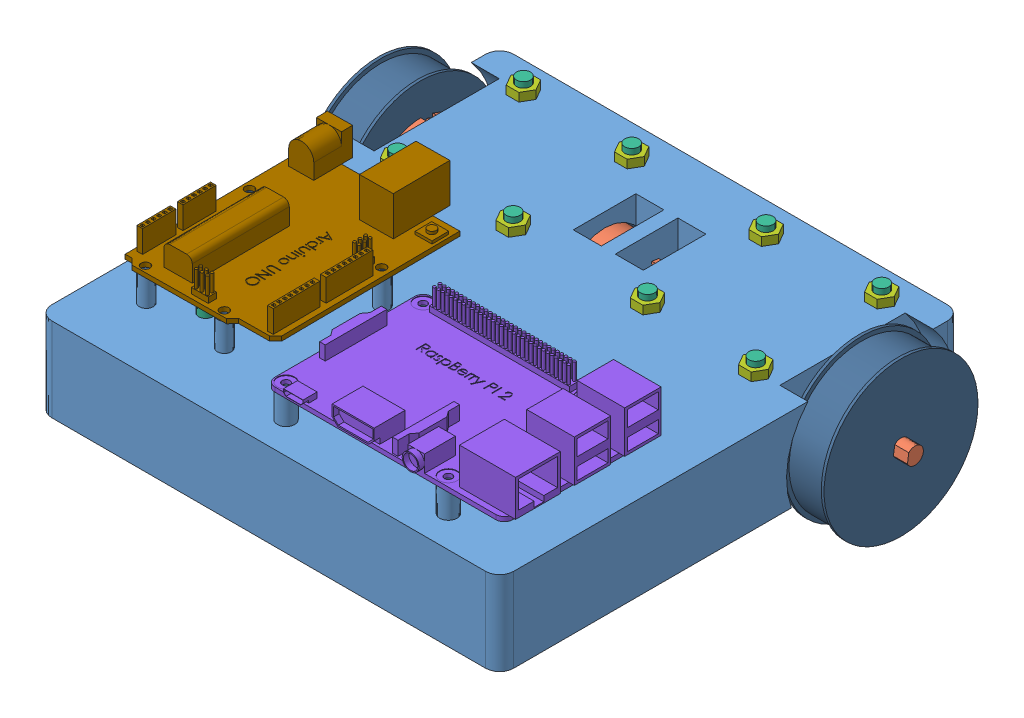
SolidWorks assembly base_robot2_ass, configuration Défaut. Lengths in mm.
Overall size (196.8 85.06 170.96).
31 component instances, 10 part files, 62 mates.
Components (placement in the parent):
- base_robot2_model-1: base_robot2_model [Défaut] at (-7.2062 -14.7881 165) size (165 40 165)
- moteur_IG320100-1: moteur_IG320100 [Défaut] at (-74.68 -4.7881 115) x (0 0.804168 0.594401) z (-1 0 0) size (32 32 94.7)
- moteur_IG320100-2: moteur_IG320100 [Défaut] at (60.2677 -4.7881 115) x (0 0.988328 -0.152341) z (1 0 0) size (32 32 94.7)
- patin_robot2_model-1: patin_robot2_model [Défaut] at (-59.7062 -24.7881 217.5) size (40 10 30)
- patin_robot2_model-2: patin_robot2_model [Défaut] at (45.2938 -24.7881 217.5) size (40 10 30)
- support_moteur_30mm-1: support_moteur_30mm [Défaut] at (11.7938 -4.7881 115) x (1 0 0) z (0 0 -1) size (10 9 52.36)
- support_moteur_30mm-2: support_moteur_30mm [Défaut] at (-26.2062 -4.7881 115) x (-1 0 0) z (0 0 1) size (10 9 52.36)
- support_moteur_32.02mm-1: support_moteur_32.02mm [Défaut] at (61.7938 -4.7881 115) x (-1 0 0) z (0 0 1) size (10 10.01 55.01)
- support_moteur_32.02mm-2: support_moteur_32.02mm [Défaut] at (-76.2062 -4.7881 115) x (1 0 0) z (0 0 -1) size (10 10.01 55.01)
- vis_5mm-1: vis_5mm [Défaut] at (16.7938 -19.7881 93.8197) x (0.187636 0 -0.982239) z (-0.982239 0 -0.187636) size (8 42.5 8)
- vis_5mm-2: vis_5mm [Défaut] at (56.7938 -19.7881 92.4972) x (-0.262741 0 -0.964866) z (-0.964866 0 0.262741) size (8 42.5 8)
- vis_5mm-3: vis_5mm [Défaut] at (16.7938 -19.7881 136.1803) x (0.587771 0 -0.809028) z (-0.809028 0 -0.587771) size (8 42.5 8)
- vis_5mm-4: vis_5mm [Défaut] at (56.7938 -19.7881 137.5028) x (-0.993067 0 0.117546) z (0.117546 0 0.993067) size (8 42.5 8)
- vis_5mm-5: vis_5mm [Défaut] at (-31.2062 -19.7881 136.1803) x (0.909957 0 -0.414702) z (-0.414702 0 -0.909957) size (8 42.5 8)
- vis_5mm-6: vis_5mm [Défaut] at (-71.2062 -19.7881 137.5028) x (0.689074 0 -0.724691) z (-0.724691 0 -0.689074) size (8 42.5 8)
- vis_5mm-7: vis_5mm [Défaut] at (-31.2062 -19.7881 93.8197) x (0.478965 0 -0.877834) z (-0.877834 0 -0.478965) size (8 42.5 8)
- vis_5mm-8: vis_5mm [Défaut] at (-71.2062 -19.7881 92.4972) x (0.586817 0 -0.80972) z (-0.80972 0 -0.586817) size (8 42.5 8)
- vis_5mm-9: vis_5mm [Défaut] at (45.2938 -19.7881 217.5) x (0.470882 0 0.882196) z (0.882196 0 -0.470882) size (8 42.5 8)
- vis_5mm-10: vis_5mm [Défaut] at (-59.7062 -19.7881 217.5) x (-0.905597 0 -0.424138) z (-0.424138 0 0.905597) size (8 42.5 8)
- ecrou_5mm_model-1: ecrou_5mm_model [Défaut] at (56.7938 15.2119 92.4972) size (9 3 7.79)
- raspberry-1: raspberry [Défaut] at (26.6692 25.2119 211.6943) size (89 17.6 58)
- arduino-1: arduino [Défaut] at (-54.4822 25.2119 192.998) x (0.009951 0 0.99995) z (-0.99995 0 0.009951) size (74.8 15.6 53.3)
- ecrou_5mm_model-2: ecrou_5mm_model [Défaut] at (-31.2062 15.2119 93.8197) size (9 3 7.79)
- ecrou_5mm_model-3: ecrou_5mm_model [Défaut] at (16.7938 15.2119 136.1803) size (9 3 7.79)
- ecrou_5mm_model-4: ecrou_5mm_model [Défaut] at (56.7938 15.2119 137.5028) size (9 3 7.79)
- ecrou_5mm_model-5: ecrou_5mm_model [Défaut] at (-31.2062 15.2119 136.1803) size (9 3 7.79)
- ecrou_5mm_model-6: ecrou_5mm_model [Défaut] at (16.7938 15.2119 93.8197) size (9 3 7.79)
- ecrou_5mm_model-7: ecrou_5mm_model [Défaut] at (-71.2062 15.2119 137.5028) size (9 3 7.79)
- ecrou_5mm_model-8: ecrou_5mm_model [Défaut] at (-71.2062 15.2119 92.4972) size (9 3 7.79)
- roue_imprimer_model-2: roue_imprimer_model [Défaut] at (-95.6062 -4.7881 115) x (1 0 0) z (0 0.804168 0.594401) size (15 55 55)
- roue_imprimer_model-3: roue_imprimer_model [Défaut] at (76.1938 -4.7881 115) x (1 0 0) z (0 -0.988328 0.152341) size (15 55 55)
Mates (geometry in assembly coordinates):
- Coaxiale1: concentric aligned: cylinder of base_robot2_model-1 through (-52.7062 -4.7881 115) axis (-1 0 0) radius 16.01; cylinder of moteur_IG320100-1 through (-95.28 -4.7881 115) axis (-1 0 0) radius 16
- Coïncidente1: coincident anti-aligned: plane of base_robot2_model-1 through (-52.7062 -4.7881 115) normal (-1 0 0); plane of moteur_IG320100-1 through (-52.7062 -4.7881 115) normal (1 0 0)
- Coaxiale3: concentric aligned: cylinder of base_robot2_model-1 through (38.2938 -4.7881 115) axis (1 0 0) radius 16.01; cylinder of moteur_IG320100-2 through (80.8677 -4.7881 115) axis (1 0 0) radius 16
- Coïncidente2: coincident anti-aligned: plane of base_robot2_model-1 through (38.2938 -4.7881 115) normal (1 0 0); plane of moteur_IG320100-2 through (38.2938 -4.7881 115) normal (-1 0 0)
- Coaxiale4: concentric aligned: cylinder of base_robot2_model-1 through (-59.7062 15.2119 217.5) axis (0 -1 0) radius 2.5; cylinder of patin_robot2_model-1 through (-59.7062 -14.7881 217.5) axis (0 -1 0) radius 2.5
- Coaxiale5: concentric aligned: cylinder of base_robot2_model-1 through (45.2938 15.2119 217.5) axis (0 -1 0) radius 2.5; cylinder of patin_robot2_model-2 through (45.2938 -14.7881 217.5) axis (0 -1 0) radius 2.5
- Coïncidente3: coincident anti-aligned: plane of base_robot2_model-1 through (-7.2062 -14.7881 165) normal (0 -1 0); plane of patin_robot2_model-1 through (-59.7062 -14.7881 217.5) normal (0 1 0)
- Coïncidente4: coincident anti-aligned: plane of base_robot2_model-1 through (-7.2062 -14.7881 165) normal (0 -1 0); plane of patin_robot2_model-2 through (45.2938 -14.7881 217.5) normal (0 1 0)
- Coaxiale6: concentric anti-aligned: cylinder of base_robot2_model-1 through (16.7938 15.2119 93.8197) axis (0 -1 0) radius 2.5; cylinder of support_moteur_30mm-1 through (16.7938 -23.7881 93.8197) axis (0 1 0) radius 2.5
- Coaxiale7: concentric anti-aligned: cylinder of moteur_IG320100-2 through (80.8677 -4.7881 115) axis (1 0 0) radius 15; cylinder of support_moteur_30mm-1 through (21.7938 -4.7881 115) axis (-1 0 0) radius 15
- Coaxiale8: concentric anti-aligned: cylinder of base_robot2_model-1 through (-31.2062 15.2119 93.8197) axis (0 -1 0) radius 2.5; cylinder of support_moteur_30mm-2 through (-31.2062 -23.7881 93.8197) axis (0 1 0) radius 2.5
- Coaxiale9: concentric anti-aligned: cylinder of moteur_IG320100-1 through (-95.28 -4.7881 115) axis (-1 0 0) radius 15; cylinder of support_moteur_30mm-2 through (-36.2062 -4.7881 115) axis (1 0 0) radius 15
- Coaxiale10: concentric anti-aligned: cylinder of base_robot2_model-1 through (56.7938 15.2119 92.4972) axis (0 -1 0) radius 2.5; cylinder of support_moteur_32.02mm-1 through (56.7938 -24.7981 92.4972) axis (0 1 0) radius 2.5
- Coaxiale12: concentric aligned: cylinder of moteur_IG320100-2 through (80.8677 -4.7881 115) axis (1 0 0) radius 16; cylinder of support_moteur_32.02mm-1 through (51.7938 -4.7881 115) axis (1 0 0) radius 16.01
- Coaxiale13: concentric aligned: cylinder of moteur_IG320100-1 through (-95.28 -4.7881 115) axis (-1 0 0) radius 16; cylinder of support_moteur_32.02mm-2 through (-66.2062 -4.7881 115) axis (-1 0 0) radius 16.01
- Coaxiale14: concentric anti-aligned: cylinder of base_robot2_model-1 through (-71.2062 15.2119 137.5028) axis (0 -1 0) radius 2.5; cylinder of support_moteur_32.02mm-2 through (-71.2062 -24.7981 137.5028) axis (0 1 0) radius 2.5
- Coaxiale16: concentric aligned: cylinder of base_robot2_model-1 through (16.7938 15.2119 93.8197) axis (0 -1 0) radius 2.5; cylinder of vis_5mm-1 through (16.7938 20.2119 93.8197) axis (0 -1 0) radius 2.5
- Coïncidente6: coincident anti-aligned: plane of support_moteur_30mm-1 through (21.7938 -19.7881 115) normal (0 -1 0); plane of vis_5mm-1 through (16.7938 -19.7881 93.8197) normal (0 1 0)
- Coaxiale17: concentric aligned: cylinder of base_robot2_model-1 through (56.7938 15.2119 92.4972) axis (0 -1 0) radius 2.5; cylinder of vis_5mm-2 through (56.7938 20.2119 92.4972) axis (0 -1 0) radius 2.5
- Coïncidente7: coincident anti-aligned: plane of support_moteur_32.02mm-1 through (51.7938 -19.7881 87.4972) normal (0 -1 0); plane of vis_5mm-2 through (56.7938 -19.7881 92.4972) normal (0 1 0)
- Coaxiale18: concentric anti-aligned: cylinder of support_moteur_32.02mm-1 through (56.7938 -24.7981 137.5028) axis (0 1 0) radius 2.5; cylinder of vis_5mm-4 through (56.7938 20.2119 137.5028) axis (0 -1 0) radius 2.5
- Coïncidente8: coincident anti-aligned: plane of support_moteur_32.02mm-1 through (51.7938 -19.7881 142.5028) normal (0 -1 0); plane of vis_5mm-4 through (56.7938 -19.7881 137.5028) normal (0 1 0)
- Coaxiale20: concentric anti-aligned: cylinder of support_moteur_30mm-1 through (16.7938 -23.7881 136.1803) axis (0 1 0) radius 2.5; cylinder of vis_5mm-3 through (16.7938 20.2119 136.1803) axis (0 -1 0) radius 2.5
- Coïncidente9: coincident anti-aligned: plane of support_moteur_30mm-1 through (21.7938 -19.7881 115) normal (0 -1 0); plane of vis_5mm-3 through (16.7938 -19.7881 136.1803) normal (0 1 0)
- Coaxiale21: concentric anti-aligned: cylinder of support_moteur_30mm-2 through (-31.2062 -23.7881 93.8197) axis (0 1 0) radius 2.5; cylinder of vis_5mm-7 through (-31.2062 20.2119 93.8197) axis (0 -1 0) radius 2.5
- Coaxiale22: concentric anti-aligned: cylinder of support_moteur_32.02mm-2 through (-71.2062 -24.7981 92.4972) axis (0 1 0) radius 2.5; cylinder of vis_5mm-8 through (-71.2062 20.2119 92.4972) axis (0 -1 0) radius 2.5
- Coaxiale23: concentric anti-aligned: cylinder of support_moteur_32.02mm-2 through (-71.2062 -24.7981 137.5028) axis (0 1 0) radius 2.5; cylinder of vis_5mm-6 through (-71.2062 20.2119 137.5028) axis (0 -1 0) radius 2.5
- Coaxiale24: concentric anti-aligned: cylinder of support_moteur_30mm-2 through (-31.2062 -23.7881 136.1803) axis (0 1 0) radius 2.5; cylinder of vis_5mm-5 through (-31.2062 20.2119 136.1803) axis (0 -1 0) radius 2.5
- Coïncidente10: coincident anti-aligned: plane of support_moteur_30mm-2 through (-36.2062 -19.7881 115) normal (0 -1 0); plane of vis_5mm-5 through (-31.2062 -19.7881 136.1803) normal (0 1 0)
- Coïncidente11: coincident anti-aligned: plane of support_moteur_32.02mm-2 through (-66.2062 -19.7881 142.5028) normal (0 -1 0); plane of vis_5mm-6 through (-71.2062 -19.7881 137.5028) normal (0 1 0)
- Coïncidente12: coincident anti-aligned: plane of support_moteur_32.02mm-2 through (-66.2062 -19.7881 87.4972) normal (0 -1 0); plane of vis_5mm-8 through (-71.2062 -19.7881 92.4972) normal (0 1 0)
- Coïncidente13: coincident anti-aligned: plane of support_moteur_30mm-2 through (-36.2062 -19.7881 115) normal (0 -1 0); plane of vis_5mm-7 through (-31.2062 -19.7881 93.8197) normal (0 1 0)
- Coaxiale25: concentric aligned: cylinder of base_robot2_model-1 through (45.2938 15.2119 217.5) axis (0 -1 0) radius 2.5; cylinder of vis_5mm-9 through (45.2938 20.2119 217.5) axis (0 -1 0) radius 2.5
- Coïncidente14: coincident anti-aligned: plane of patin_robot2_model-2 through (45.2938 -19.7881 217.5) normal (0 -1 0); plane of vis_5mm-9 through (45.2938 -19.7881 217.5) normal (0 1 0)
- Coaxiale26: concentric aligned: cylinder of base_robot2_model-1 through (-59.7062 15.2119 217.5) axis (0 -1 0) radius 2.5; cylinder of vis_5mm-10 through (-59.7062 20.2119 217.5) axis (0 -1 0) radius 2.5
- Coïncidente15: coincident anti-aligned: plane of patin_robot2_model-1 through (-59.7062 -19.7881 217.5) normal (0 -1 0); plane of vis_5mm-10 through (-59.7062 -19.7881 217.5) normal (0 1 0)
- Coaxiale27: concentric aligned: cylinder of vis_5mm-2 through (56.7938 20.2119 92.4972) axis (0 -1 0) radius 2.5; cylinder of ecrou_5mm_model-1 through (56.7938 18.2119 92.4972) axis (0 -1 0) radius 2.5
- Coïncidente16: coincident anti-aligned: plane of base_robot2_model-1 through (-7.2062 15.2119 165) normal (0 1 0); plane of ecrou_5mm_model-1 through (56.7938 15.2119 92.4972) normal (0 -1 0)
- Coaxiale28: concentric aligned: cylinder of base_robot2_model-1 through (45.6692 25.2119 187.1943) axis (0 -1 0) radius 1.375; cylinder of raspberry-1 through (45.6692 26.8119 187.1943) axis (0 -1 0) radius 1.375
- Coïncidente17: coincident anti-aligned: plane of base_robot2_model-1 through (45.6692 25.2119 187.1943) normal (0 1 0); plane of raspberry-1 through (66.1692 25.2119 236.6943) normal (0 -1 0)
- Coaxiale29: concentric aligned: cylinder of base_robot2_model-1 through (-45.5399 25.2119 225.0106) axis (0 -1 0) radius 1.6; cylinder of arduino-1 through (-45.5399 26.8119 225.0106) axis (0 -1 0) radius 1.6
- Coïncidente18: coincident anti-aligned: plane of base_robot2_model-1 through (-73.4399 25.2119 225.0106) normal (0 1 0); plane of arduino-1 through (-54.4822 25.2119 192.998) normal (0 -1 0)
- Coaxiale30: concentric aligned: cylinder of vis_5mm-4 through (56.7938 20.2119 137.5028) axis (0 -1 0) radius 2.5; cylinder of ecrou_5mm_model-4 through (56.7938 18.2119 137.5028) axis (0 -1 0) radius 2.5
- Coaxiale31: concentric aligned: cylinder of vis_5mm-3 through (16.7938 20.2119 136.1803) axis (0 -1 0) radius 2.5; cylinder of ecrou_5mm_model-3 through (16.7938 18.2119 136.1803) axis (0 -1 0) radius 2.5
- Coaxiale32: concentric aligned: cylinder of vis_5mm-1 through (16.7938 20.2119 93.8197) axis (0 -1 0) radius 2.5; cylinder of ecrou_5mm_model-6 through (16.7938 18.2119 93.8197) axis (0 -1 0) radius 2.5
- Coaxiale33: concentric aligned: cylinder of vis_5mm-8 through (-71.2062 20.2119 92.4972) axis (0 -1 0) radius 2.5; cylinder of ecrou_5mm_model-8 through (-71.2062 18.2119 92.4972) axis (0 -1 0) radius 2.5
- Coïncidente19: coincident anti-aligned: cylinder of vis_5mm-6 through (-71.2062 20.2119 137.5028) axis (0 -1 0) radius 2.5; circle of ecrou_5mm_model-7
- Coaxiale34: concentric aligned: cylinder of vis_5mm-5 through (-31.2062 20.2119 136.1803) axis (0 -1 0) radius 2.5; cylinder of ecrou_5mm_model-5 through (-31.2062 18.2119 136.1803) axis (0 -1 0) radius 2.5
- Coaxiale35: concentric aligned: cylinder of vis_5mm-7 through (-31.2062 20.2119 93.8197) axis (0 -1 0) radius 2.5; cylinder of ecrou_5mm_model-2 through (-31.2062 18.2119 93.8197) axis (0 -1 0) radius 2.5
- Coïncidente20: coincident anti-aligned: plane of base_robot2_model-1 through (-7.2062 15.2119 165) normal (0 1 0); plane of ecrou_5mm_model-4 through (56.7938 15.2119 137.5028) normal (0 -1 0)
- Coïncidente21: coincident anti-aligned: plane of base_robot2_model-1 through (-7.2062 15.2119 165) normal (0 1 0); plane of ecrou_5mm_model-6 through (16.7938 15.2119 93.8197) normal (0 -1 0)
- Coïncidente22: coincident anti-aligned: plane of base_robot2_model-1 through (-7.2062 15.2119 165) normal (0 1 0); plane of ecrou_5mm_model-3 through (16.7938 15.2119 136.1803) normal (0 -1 0)
- Coïncidente23: coincident anti-aligned: plane of base_robot2_model-1 through (-7.2062 15.2119 165) normal (0 1 0); plane of ecrou_5mm_model-5 through (-31.2062 15.2119 136.1803) normal (0 -1 0)
- Coïncidente24: coincident anti-aligned: plane of base_robot2_model-1 through (-7.2062 15.2119 165) normal (0 1 0); plane of ecrou_5mm_model-8 through (-71.2062 15.2119 92.4972) normal (0 -1 0)
- Coïncidente25: coincident anti-aligned: plane of base_robot2_model-1 through (-7.2062 15.2119 165) normal (0 1 0); plane of ecrou_5mm_model-2 through (-31.2062 15.2119 93.8197) normal (0 -1 0)
- Coïncidente26: coincident anti-aligned: plane of base_robot2_model-1 through (-7.2062 15.2119 165) normal (0 1 0); plane of ecrou_5mm_model-7 through (-71.2062 15.2119 137.5028) normal (0 -1 0)
- Coaxiale36: concentric anti-aligned: cylinder of moteur_IG320100-1 through (-95.28 -4.7881 115) axis (-1 0 0) radius 3; cylinder of roue_imprimer_model-2 through (-100.6062 -4.7881 115) axis (1 0 0) radius 3
- Coïncidente27: coincident anti-aligned: plane of moteur_IG320100-1 through (-93.6062 -4.6356 112.0039) normal (0 0.594401 -0.804168); plane of roue_imprimer_model-2 through (-100.6062 -1.9685 113.9753) normal (0 -0.594401 0.804168)
- Distance1: distance = 5 mm aligned: plane of moteur_IG320100-1 through (-105.6062 -4.7881 115) normal (-1 0 0); plane of roue_imprimer_model-2 through (-100.6062 -4.7881 115) normal (-1 0 0)
- Coïncidente29: coincident anti-aligned: plane of moteur_IG320100-2 through (79.1938 -6.0462 117.7234) normal (0 0.152341 0.988328); plane of roue_imprimer_model-3 through (71.1938 -6.0462 117.7234) normal (0 -0.152341 -0.988328)
- Coaxiale37: concentric aligned: cylinder of moteur_IG320100-2 through (80.8677 -4.7881 115) axis (1 0 0) radius 3; cylinder of roue_imprimer_model-3 through (71.1938 -4.7881 115) axis (1 0 0) radius 3
- Distance2: distance = 5 mm aligned: plane of roue_imprimer_model-3 through (86.1938 -4.7881 115) normal (1 0 0); plane of moteur_IG320100-2 through (91.1938 -4.7881 115) normal (1 0 0)
